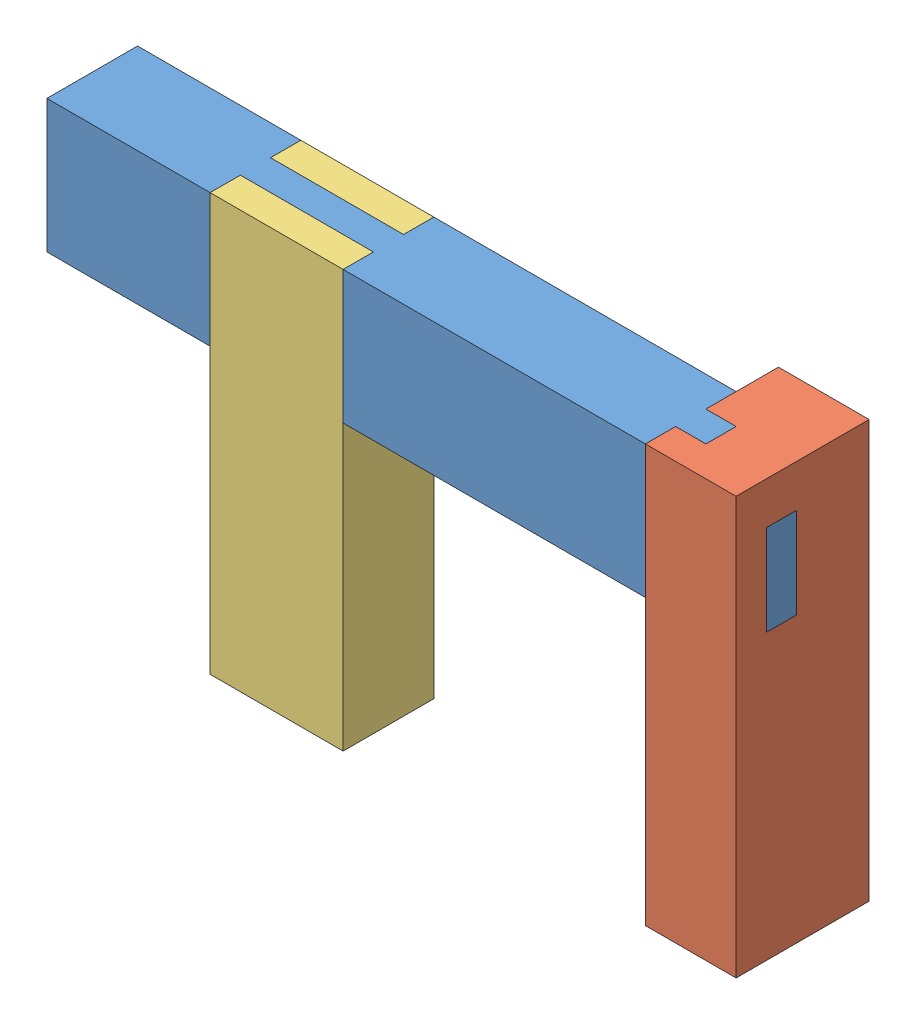
SolidWorks assembly Assem1, configuration Default. Lengths in mm.
Overall size (234 144 44).
3 component instances, 3 part files, 6 mates.
Components (placement in the parent):
- Long Piece-1: Long Piece [Default] at (-13.6127 8.281 1.5573) size (234 44 30)
- Mortice-1: Mortice [Default] at (88.3873 -41.719 -5.4427) size (30 144 44)
- Bridle Joint-1: Bridle Joint [Default] at (-48.6127 -41.719 1.5573) size (44 144 30)
Mates (geometry in assembly coordinates):
- Coincident1: coincident: plane of Long Piece-1 through (73.3873 -13.72 16.5573) normal (1 0 0); plane of Mortice-1 through (73.3873 30.281 -55.1602) normal (-1 0 0)
- Coincident3: coincident: line of Long Piece-1 through (73.3873 30.281 6.5573) axis (0 0 1); line of Mortice-1 through (73.3873 30.281 6.5573) axis (0 0 1)
- Coincident4: coincident anti-aligned: line of Long Piece-1 through (73.3873 -13.719 16.5573) axis (0 1 0); line of Mortice-1 through (73.3873 30.281 16.5573) axis (0 -1 0)
- Coincident5: coincident: plane of Bridle Joint-1 through (-70.6127 30.281 -3.4427) normal (0 0 1); plane of Long Piece-1 through (-70.6127 -13.72 -3.4427) normal (0 0 -1)
- Coincident6: coincident: plane of Long Piece-1 through (-26.6127 -13.72 16.5573) normal (-1 0 0); plane of Bridle Joint-1 through (-26.6127 -113.719 16.5573) normal (1 0 0)
- Coincident7: coincident anti-aligned: line of Long Piece-1 through (-26.6127 30.281 6.5573) axis (-1 0 0); line of Bridle Joint-1 through (-70.6127 30.281 6.5573) axis (1 0 0)
